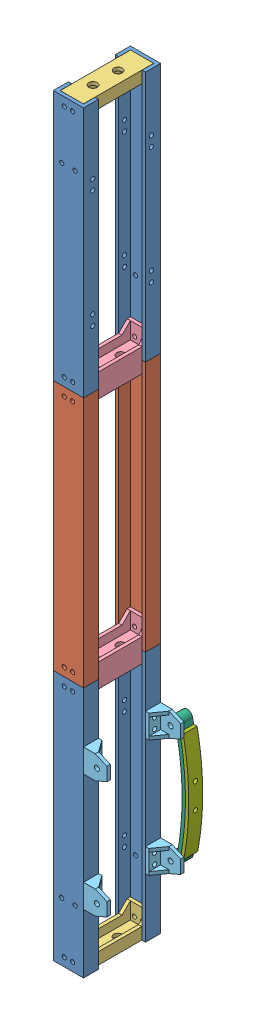
SolidWorks assembly Chassis Assembly, configuration Default. Lengths in mm.
Overall size (34.84 450 54.3).
16 component instances, 7 part files, 32 mates.
Components (placement in the parent):
- chassis frame 3-1: chassis frame 3 [Default] at origin size (18 150 9)
- chassis frame 2-1: chassis frame 2 [Default] at (0 -150 0) size (18 150 9)
- chassis frame connector-1: chassis frame connector [Default] at (0 148 -18.519) x (0 0 -1) z (1 0 0) size (42 12 13.8)
- chassis frame connector2-1: chassis frame connector2 [Default] at (0 -2 -18.5) x (0 0 1) z (-1 0 0) size (42 24 14)
- chassis frame connector2-4: chassis frame connector2 [Default] at (0 -152 -18.5) x (0 0 1) z (-1 0 0) size (42 24 14)
- chassis frame connector-3: chassis frame connector [Default] at (-0.1 -298 -18.5) x (0 0 -1) z (-1 0 0) size (42 12 13.8)
- chassis frame 3-5: chassis frame 3 [Default] at (0 150 -37.019) x (1 0 0) z (0 0 -1) size (18 150 9)
- chassis frame 2-3: chassis frame 2 [Default] at (0 0 -37) x (1 0 0) z (0 0 -1) size (18 150 9)
- chassis frame 3-6: chassis frame 3 [Default] at (0 -150 -37) x (1 0 0) z (0 0 -1) size (18 150 9)
- leafspring connector-3: leafspring connector [Default] at (9 -257.5 -37) x (0 1 0) z (0 0 -1) size (14 14 9)
- leafspring connector-4: leafspring connector [Default] at (9 -187.5 -37) x (0 1 0) z (0 0 -1) size (14 14 9)
- chassis frame 3-7: chassis frame 3 [Default] at (0 -150 0) x (-1 0 0) z (0 0 1) size (18 150 9)
- leafspring connector-5: leafspring connector [Default] at (9 -257.5 0) x (0 -1 0) z (0 0 1) size (14 14 9)
- leafspring connector-8: leafspring connector [Default] at (9 -187.5 0) x (0 -1 0) z (0 0 1) size (14 14 9)
- leafspring75mm-1: leafspring75mm [Default] at (21.1426 -222.5 -49.8) x (0 1 0) z (1 0 0) size (76.5 8.3 10.47)
- leafspring65mm-1: leafspring65mm [Default] at (23.1424 -222.4754 -49.8) x (0 1 0) z (1 0 0) size (64.64 8.3 5.37)
Mates (geometry in assembly coordinates):
- Coincident8: coordinate: point of chassis frame 3-1
- Coincident15: coincident anti-aligned: plane of chassis frame 3-1 through (0 0 0) normal (0 -1 0); plane of chassis frame 2-1 through (0 0 0) normal (0 1 0)
- Coincident17: coincident anti-aligned: plane of chassis frame 3-1 through (0 0 0) normal (0 -1 0); plane of chassis frame 2-1 through (0 0 0) normal (0 1 0)
- Coincident21: coincident aligned: plane of chassis frame 3-1 through (-9 150 -4.5) normal (0 0 -1); plane of chassis frame 2-1 through (-9 0 -4.5) normal (0 0 -1)
- Coincident22: coincident aligned: plane of chassis frame 3-1 through (-9 150 -4.5) normal (-1 0 0); plane of chassis frame 2-1 through (-9 0 -4.5) normal (-1 0 0)
- Parallel9: parallel anti-aligned: plane of chassis frame 3-1 through (7 150 -4.5) normal (-1 0 0); plane of chassis frame connector-1 through (6.9 150 2.481) normal (1 0 0)
- Coincident28: coincident aligned: plane of chassis frame 3-1 through (0 150 0) normal (0 1 0); plane of chassis frame connector-1 through (0 150 -18.519) normal (0 1 0)
- Concentric1: concentric aligned: cylinder of chassis frame 3-1 through (2.5 145 12.5) axis (0 0 -1) radius 1.25; cylinder of chassis frame connector-1 through (2.5 145 2.481) axis (0 0 -1) radius 1.25
- Coincident30: coincident anti-aligned: plane of chassis frame 2-1 through (-7 0 2.5) normal (0 0 -1); plane of chassis frame connector2-1 through (7 2 2.5) normal (0 0 1)
- Concentric2: concentric aligned: cylinder of chassis frame 3-1 through (-2.5 5 12.5) axis (0 0 -1) radius 1.25; cylinder of chassis frame connector2-1 through (-2.5 5 10.5) axis (0 0 -1) radius 1.25
- Coincident47: coincident anti-aligned: plane of chassis frame 2-1 through (-7 0 2.5) normal (0 0 -1); plane of chassis frame connector2-4 through (7 -148 2.5) normal (0 0 1)
- Coincident48: coincident anti-aligned: plane of chassis frame 2-1 through (7 0 -4.5) normal (-1 0 0); plane of chassis frame connector2-4 through (7 -148 -39.5) normal (1 0 0)
- Concentric7: concentric aligned: cylinder of chassis frame 2-1 through (2.5 -145 12.5) axis (0 0 -1) radius 1.25; cylinder of chassis frame connector2-4 through (2.5 -145 10.5) axis (0 0 -1) radius 1.25
- Concentric8: concentric aligned: cylinder of chassis frame connector-1 through (-2.5 145 -39.519) axis (0 0 1) radius 1.25; cylinder of chassis frame 3-5 through (-2.5 145 -49.519) axis (0 0 1) radius 1.25
- Coincident57: coincident anti-aligned: plane of chassis frame connector-1 through (-6.9 150 -39.519) normal (0 0 -1); plane of chassis frame 3-5 through (-7 0 -39.519) normal (0 0 1)
- Concentric9: concentric aligned: cylinder of chassis frame connector2-1 through (-2.5 -5 -39.5) axis (0 0 1) radius 1.25; cylinder of chassis frame 2-3 through (-2.5 -5 -49.5) axis (0 0 1) radius 1.25
- Coincident58: coincident anti-aligned: plane of chassis frame connector2-4 through (7 -148 -39.5) normal (0 0 -1); plane of chassis frame 2-3 through (-7 -150 -39.5) normal (0 0 1)
- Coincident59: coincident anti-aligned: plane of chassis frame 2-3 through (0 -150 -37) normal (0 -1 0); plane of chassis frame 3-6 through (0 -150 -37) normal (0 1 0)
- Coincident61: coincident anti-aligned: plane of chassis frame connector2-4 through (7 -148 -39.5) normal (0 0 -1); plane of chassis frame 3-6 through (-7 -300 -39.5) normal (0 0 1)
- Coincident62: coincident aligned: plane of chassis frame 2-3 through (-9 -150 -32.5) normal (-1 0 0); plane of chassis frame 3-6 through (-9 -300 -32.5) normal (-1 0 0)
- Coincident63: coincident anti-aligned: plane of chassis frame 3-6 through (9 -300 -32.5) normal (1 0 0); plane of leafspring connector-3 through (9 -257.5 -37) normal (-1 0 0)
- Concentric12: concentric aligned: cylinder of chassis frame 3-6 through (-9 -260.5 -36) axis (1 0 0) radius 1.25; cylinder of leafspring connector-3 through (9 -260.5 -36) axis (1 0 0) radius 1.25
- Coincident64: coincident anti-aligned: plane of chassis frame 3-6 through (9 -300 -32.5) normal (1 0 0); plane of leafspring connector-4 through (9 -187.5 -37) normal (-1 0 0)
- Concentric13: concentric aligned: cylinder of chassis frame 3-6 through (-9 -190.5 -36) axis (1 0 0) radius 1.25; cylinder of leafspring connector-4 through (9 -190.5 -36) axis (1 0 0) radius 1.25
- Concentric14: concentric aligned: cylinder of chassis frame connector2-4 through (-2.5 -155 2.5) axis (0 0 -1) radius 1.25; cylinder of chassis frame 3-7 through (-2.5 -155 12.5) axis (0 0 -1) radius 1.25
- Coincident65: coincident aligned: plane of chassis frame 2-1 through (-9 0 -4.5) normal (0 0 -1); plane of chassis frame 3-7 through (-9 -300 -4.5) normal (0 0 -1)
- Concentric15: concentric anti-aligned: cylinder of chassis frame 3-7 through (9 -184.5 -1) axis (-1 0 0) radius 1.25; cylinder of leafspring connector-8 through (9 -184.5 -1) axis (1 0 0) radius 1.25
- Concentric16: concentric anti-aligned: cylinder of chassis frame 3-7 through (9 -254.5 -1) axis (-1 0 0) radius 1.25; cylinder of leafspring connector-5 through (9 -254.5 -1) axis (1 0 0) radius 1.25
- Concentric17: concentric aligned: cylinder of leafspring connector-3 through (17 -257.5 -35.2574) axis (0 0 -1) radius 1.5; cylinder of leafspring75mm-1 through (17 -257.5 -41.5) axis (0 0 -1) radius 1.25
- Parallel23: parallel aligned: cylinder of leafspring connector-4 through (17 -187.5 -35.2574) axis (0 0 -1) radius 1.5; cylinder of leafspring75mm-1 through (16.622 -187.5 -41.5) axis (0 0 -1) radius 1.25
- Tangent3: tangent aligned: cylinder of leafspring75mm-1 through (-143.368 -223.365 -41.5) axis (0 0 -1) radius 167.2107; cylinder of leafspring65mm-1 through (-141.3682 -223.3404 -41.5) axis (0 0 -1) radius 165.2107
- Coincident66: coincident aligned: plane of leafspring75mm-1 through (-143.368 -223.365 -49.8) normal (0 0 -1); plane of leafspring65mm-1 through (-141.3682 -223.3404 -49.8) normal (0 0 -1)
